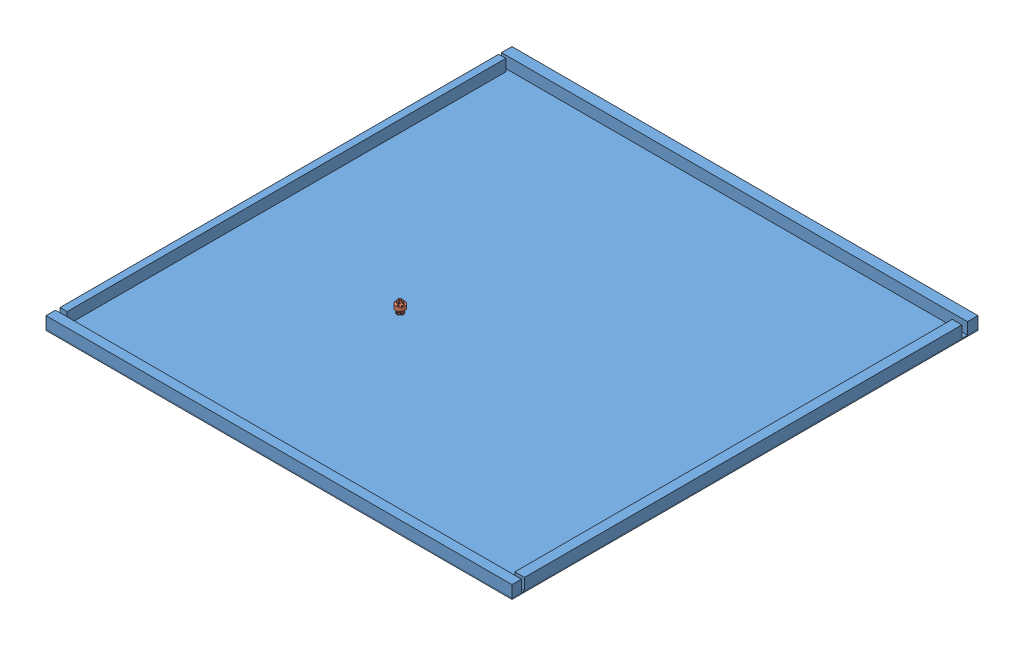
SolidWorks assembly SinlgeBotAssem, configuration Default. Lengths in mm.
Overall size (4000 116.11 4000).
3 component instances, 3 part files, 3 mates.
Components (placement in the parent):
- graound-1: graound [Default] at (250 0 -250) x (1 0 0) z (0 1 0) size (4000 4000 110)
- single_bot1-1: single_bot1 [Default] at (1478.2549 -106.9208 -1716.9522) x (0.992949 0.083346 -0.084297) z (-0.084297 0.99641 -0.007776) size (79.61 77.63 98.49)
- leg-1: leg [Default] at (1402.9825 24.7718 -1634.5602) x (0.55308 0 -0.833128) z (0.833128 0 0.55308) size (25.5 15.75 8)
Mates (geometry in assembly coordinates):
- Parallel22: parallel anti-aligned: plane of graound-1 through (250 10 -250) normal (0 1 0); plane of single_bot1-1 through (1412.8219 17.7718 -1596.1183) normal (0 -1 0)
- Concentric31: concentric aligned: cylinder of single_bot1-1 through (1402.9825 24.7718 -1634.5602) axis (0.833128 0 0.55308) radius 1.5; cylinder of leg-1 through (1402.9825 24.7718 -1634.5602) axis (0.833128 0 0.55308) radius 1.575
- Coincident81: coincident anti-aligned: plane of single_bot1-1 through (1401.8757 22.7708 -1632.8931) normal (0.833128 0 0.55308); plane of leg-1 through (1402.9825 24.7718 -1634.5602) normal (-0.833128 0 -0.55308)
